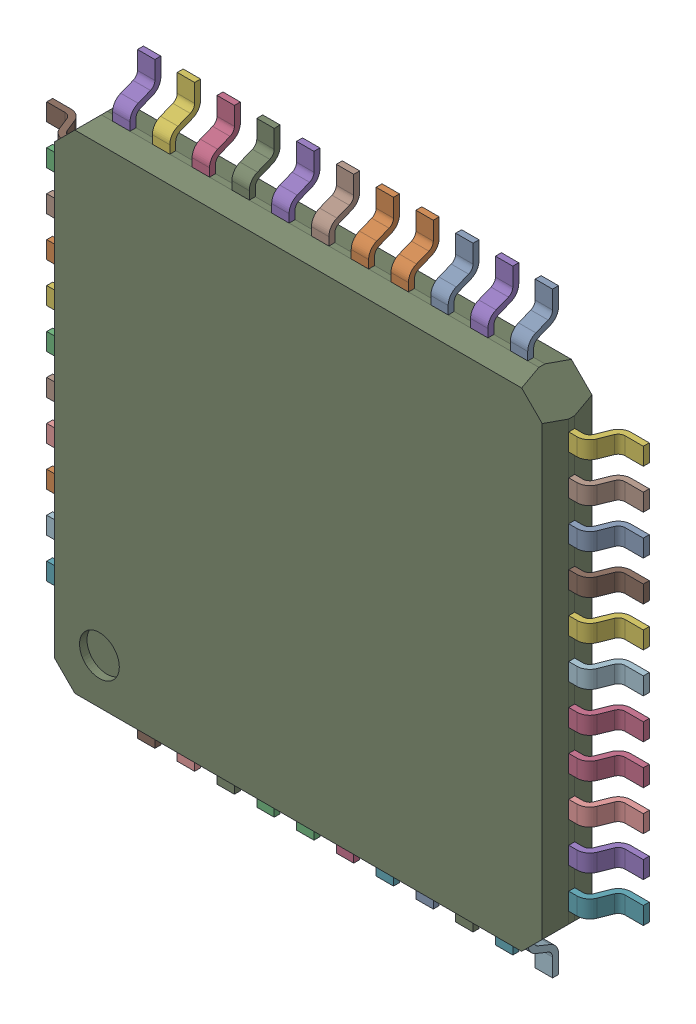
SolidWorks assembly User_Library-TQFP-44, configuration Défaut. Lengths in mm.
Overall size (12 12 1.06).
45 component instances, 2 part files, 0 mates.
Components (placement in the parent):
- User_Library-TQFP-44_pins_TQFP_pin_TQFP_035_1-1: User_Library-TQFP-44_pins_TQFP_pin_TQFP_035_1 [Défaut] at (6 2.225 -0.5) x (0 1 0) z (1 0 0) size (0.35 0.62 1)
- User_Library-TQFP-44_pins_TQFP_pin_TQFP_035_1-2: User_Library-TQFP-44_pins_TQFP_pin_TQFP_035_1 [Défaut] at (-6 -2.225 -0.5) x (0 -1 0) z (-1 0 0) size (0.35 0.62 1)
- User_Library-TQFP-44_pins_TQFP_pin_TQFP_035_1-3: User_Library-TQFP-44_pins_TQFP_pin_TQFP_035_1 [Défaut] at (-6 3.375 -0.5) x (0 -1 0) z (-1 0 0) size (0.35 0.62 1)
- User_Library-TQFP-44_pins_TQFP_pin_TQFP_035_1-4: User_Library-TQFP-44_pins_TQFP_pin_TQFP_035_1 [Défaut] at (6 -0.975 -0.5) x (0 1 0) z (1 0 0) size (0.35 0.62 1)
- User_Library-TQFP-44_pins_TQFP_pin_TQFP_035_1-5: User_Library-TQFP-44_pins_TQFP_pin_TQFP_035_1 [Défaut] at (3.375 6 -0.5) x (-1 0 0) z (0 1 0) size (0.35 0.62 1)
- User_Library-TQFP-44_pins_TQFP_pin_TQFP_035_1-6: User_Library-TQFP-44_pins_TQFP_pin_TQFP_035_1 [Défaut] at (-6 0.975 -0.5) x (0 -1 0) z (-1 0 0) size (0.35 0.62 1)
- User_Library-TQFP-44_pins_TQFP_pin_TQFP_035_1-7: User_Library-TQFP-44_pins_TQFP_pin_TQFP_035_1 [Défaut] at (0.625 -6 -0.5) x (1 0 0) z (0 -1 0) size (0.35 0.62 1)
- User_Library-TQFP-44_pins_TQFP_pin_TQFP_035_1-8: User_Library-TQFP-44_pins_TQFP_pin_TQFP_035_1 [Défaut] at (0.175 6 -0.5) x (-1 0 0) z (0 1 0) size (0.35 0.62 1)
- User_Library-TQFP-44_pins_TQFP_pin_TQFP_035_1-9: User_Library-TQFP-44_pins_TQFP_pin_TQFP_035_1 [Défaut] at (-2.575 -6 -0.5) x (1 0 0) z (0 -1 0) size (0.35 0.62 1)
- User_Library-TQFP-44_pins_TQFP_pin_TQFP_035_1-10: User_Library-TQFP-44_pins_TQFP_pin_TQFP_035_1 [Défaut] at (-3.375 -6 -0.5) x (1 0 0) z (0 -1 0) size (0.35 0.62 1)
- User_Library-TQFP-44_pins_TQFP_pin_TQFP_035_1-11: User_Library-TQFP-44_pins_TQFP_pin_TQFP_035_1 [Défaut] at (6 1.425 -0.5) x (0 1 0) z (1 0 0) size (0.35 0.62 1)
- User_Library-TQFP-44_pins_TQFP_pin_TQFP_035_1-12: User_Library-TQFP-44_pins_TQFP_pin_TQFP_035_1 [Défaut] at (-6 -3.025 -0.5) x (0 -1 0) z (-1 0 0) size (0.35 0.62 1)
- User_Library-TQFP-44_pins_TQFP_pin_TQFP_035_1-13: User_Library-TQFP-44_pins_TQFP_pin_TQFP_035_1 [Défaut] at (2.575 6 -0.5) x (-1 0 0) z (0 1 0) size (0.35 0.62 1)
- User_Library-TQFP-44_pins_TQFP_pin_TQFP_035_1-14: User_Library-TQFP-44_pins_TQFP_pin_TQFP_035_1 [Défaut] at (1.775 6 -0.5) x (-1 0 0) z (0 1 0) size (0.35 0.62 1)
- User_Library-TQFP-44_pins_TQFP_pin_TQFP_035_1-15: User_Library-TQFP-44_pins_TQFP_pin_TQFP_035_1 [Défaut] at (-0.975 -6 -0.5) x (1 0 0) z (0 -1 0) size (0.35 0.62 1)
- User_Library-TQFP-44_pins_TQFP_pin_TQFP_035_1-16: User_Library-TQFP-44_pins_TQFP_pin_TQFP_035_1 [Défaut] at (-0.175 -6 -0.5) x (1 0 0) z (0 -1 0) size (0.35 0.62 1)
- User_Library-TQFP-44_pins_TQFP_pin_TQFP_035_1-17: User_Library-TQFP-44_pins_TQFP_pin_TQFP_035_1 [Défaut] at (-0.625 6 -0.5) x (-1 0 0) z (0 1 0) size (0.35 0.62 1)
- User_Library-TQFP-44_pins_TQFP_pin_TQFP_035_1-18: User_Library-TQFP-44_pins_TQFP_pin_TQFP_035_1 [Défaut] at (-3.025 6 -0.5) x (-1 0 0) z (0 1 0) size (0.35 0.62 1)
- User_Library-TQFP-44_pins_TQFP_pin_TQFP_035_1-19: User_Library-TQFP-44_pins_TQFP_pin_TQFP_035_1 [Défaut] at (6 -4.175 -0.5) x (0 1 0) z (1 0 0) size (0.35 0.62 1)
- User_Library-TQFP-44_pins_TQFP_pin_TQFP_035_1-20: User_Library-TQFP-44_pins_TQFP_pin_TQFP_035_1 [Défaut] at (6 3.025 -0.5) x (0 1 0) z (1 0 0) size (0.35 0.62 1)
- User_Library-TQFP-44_pins_TQFP_pin_TQFP_035_1-21: User_Library-TQFP-44_pins_TQFP_pin_TQFP_035_1 [Défaut] at (2.225 -6 -0.5) x (1 0 0) z (0 -1 0) size (0.35 0.62 1)
- User_Library-TQFP-44_pins_TQFP_pin_TQFP_035_1-22: User_Library-TQFP-44_pins_TQFP_pin_TQFP_035_1 [Défaut] at (-6 -1.425 -0.5) x (0 -1 0) z (-1 0 0) size (0.35 0.62 1)
- User_Library-TQFP-44_pins_TQFP_pin_TQFP_035_1-23: User_Library-TQFP-44_pins_TQFP_pin_TQFP_035_1 [Défaut] at (-6 4.175 -0.5) x (0 -1 0) z (-1 0 0) size (0.35 0.62 1)
- User_Library-TQFP-44_pins_TQFP_pin_TQFP_035_1-24: User_Library-TQFP-44_pins_TQFP_pin_TQFP_035_1 [Défaut] at (6 -0.175 -0.5) x (0 1 0) z (1 0 0) size (0.35 0.62 1)
- User_Library-TQFP-44_pins_TQFP_pin_TQFP_035_1-25: User_Library-TQFP-44_pins_TQFP_pin_TQFP_035_1 [Défaut] at (4.175 6 -0.5) x (-1 0 0) z (0 1 0) size (0.35 0.62 1)
- User_Library-TQFP-44_pins_TQFP_pin_TQFP_035_1-26: User_Library-TQFP-44_pins_TQFP_pin_TQFP_035_1 [Défaut] at (-6 1.775 -0.5) x (0 -1 0) z (-1 0 0) size (0.35 0.62 1)
- User_Library-TQFP-44_pins_TQFP_pin_TQFP_035_1-27: User_Library-TQFP-44_pins_TQFP_pin_TQFP_035_1 [Défaut] at (-6 0.175 -0.5) x (0 -1 0) z (-1 0 0) size (0.35 0.62 1)
- User_Library-TQFP-44_pins_TQFP_pin_TQFP_035_1-28: User_Library-TQFP-44_pins_TQFP_pin_TQFP_035_1 [Défaut] at (6 -1.775 -0.5) x (0 1 0) z (1 0 0) size (0.35 0.62 1)
- User_Library-TQFP-44_pins_TQFP_pin_TQFP_035_1-29: User_Library-TQFP-44_pins_TQFP_pin_TQFP_035_1 [Défaut] at (-3.825 6 -0.5) x (-1 0 0) z (0 1 0) size (0.35 0.62 1)
- User_Library-TQFP-44_pins_TQFP_pin_TQFP_035_1-30: User_Library-TQFP-44_pins_TQFP_pin_TQFP_035_1 [Défaut] at (6 0.625 -0.5) x (0 1 0) z (1 0 0) size (0.35 0.62 1)
- User_Library-TQFP-44_pins_TQFP_pin_TQFP_035_1-31: User_Library-TQFP-44_pins_TQFP_pin_TQFP_035_1 [Défaut] at (-6 -3.825 -0.5) x (0 -1 0) z (-1 0 0) size (0.35 0.62 1)
- User_Library-TQFP-44_pins_TQFP_pin_TQFP_035_1-32: User_Library-TQFP-44_pins_TQFP_pin_TQFP_035_1 [Défaut] at (-6 2.575 -0.5) x (0 -1 0) z (-1 0 0) size (0.35 0.62 1)
- User_Library-TQFP-44_pins_TQFP_pin_TQFP_035_1-33: User_Library-TQFP-44_pins_TQFP_pin_TQFP_035_1 [Défaut] at (-1.425 6 -0.5) x (-1 0 0) z (0 1 0) size (0.35 0.62 1)
- User_Library-TQFP-44_pins_TQFP_pin_TQFP_035_1-34: User_Library-TQFP-44_pins_TQFP_pin_TQFP_035_1 [Défaut] at (6 -2.575 -0.5) x (0 1 0) z (1 0 0) size (0.35 0.62 1)
- User_Library-TQFP-44_pins_TQFP_pin_TQFP_035_1-35: User_Library-TQFP-44_pins_TQFP_pin_TQFP_035_1 [Défaut] at (-4.175 -6 -0.5) x (1 0 0) z (0 -1 0) size (0.35 0.62 1)
- User_Library-TQFP-44_pins_TQFP_pin_TQFP_035_1-36: User_Library-TQFP-44_pins_TQFP_pin_TQFP_035_1 [Défaut] at (3.825 -6 -0.5) x (1 0 0) z (0 -1 0) size (0.35 0.62 1)
- User_Library-TQFP-44_pins_TQFP_pin_TQFP_035_1-37: User_Library-TQFP-44_pins_TQFP_pin_TQFP_035_1 [Défaut] at (1.425 -6 -0.5) x (1 0 0) z (0 -1 0) size (0.35 0.62 1)
- User_Library-TQFP-44_pins_TQFP_pin_TQFP_035_1-38: User_Library-TQFP-44_pins_TQFP_pin_TQFP_035_1 [Défaut] at (0.975 6 -0.5) x (-1 0 0) z (0 1 0) size (0.35 0.62 1)
- User_Library-TQFP-44_pins_TQFP_pin_TQFP_035_1-39: User_Library-TQFP-44_pins_TQFP_pin_TQFP_035_1 [Défaut] at (-1.775 -6 -0.5) x (1 0 0) z (0 -1 0) size (0.35 0.62 1)
- User_Library-TQFP-44_pins_TQFP_pin_TQFP_035_1-40: User_Library-TQFP-44_pins_TQFP_pin_TQFP_035_1 [Défaut] at (-2.225 6 -0.5) x (-1 0 0) z (0 1 0) size (0.35 0.62 1)
- User_Library-TQFP-44_pins_TQFP_pin_TQFP_035_1-41: User_Library-TQFP-44_pins_TQFP_pin_TQFP_035_1 [Défaut] at (6 -3.375 -0.5) x (0 1 0) z (1 0 0) size (0.35 0.62 1)
- User_Library-TQFP-44_pins_TQFP_pin_TQFP_035_1-42: User_Library-TQFP-44_pins_TQFP_pin_TQFP_035_1 [Défaut] at (6 3.825 -0.5) x (0 1 0) z (1 0 0) size (0.35 0.62 1)
- User_Library-TQFP-44_pins_TQFP_pin_TQFP_035_1-43: User_Library-TQFP-44_pins_TQFP_pin_TQFP_035_1 [Défaut] at (3.025 -6 -0.5) x (1 0 0) z (0 -1 0) size (0.35 0.62 1)
- User_Library-TQFP-44_pins_TQFP_pin_TQFP_035_1-44: User_Library-TQFP-44_pins_TQFP_pin_TQFP_035_1 [Défaut] at (-6 -0.625 -0.5) x (0 -1 0) z (-1 0 0) size (0.35 0.62 1)
- User_Library-TQFP-44_body_10x1_TQFP_10x10_1-1: User_Library-TQFP-44_body_10x1_TQFP_10x10_1 [Défaut] at (0 0 -0.5) size (10 10 1)
